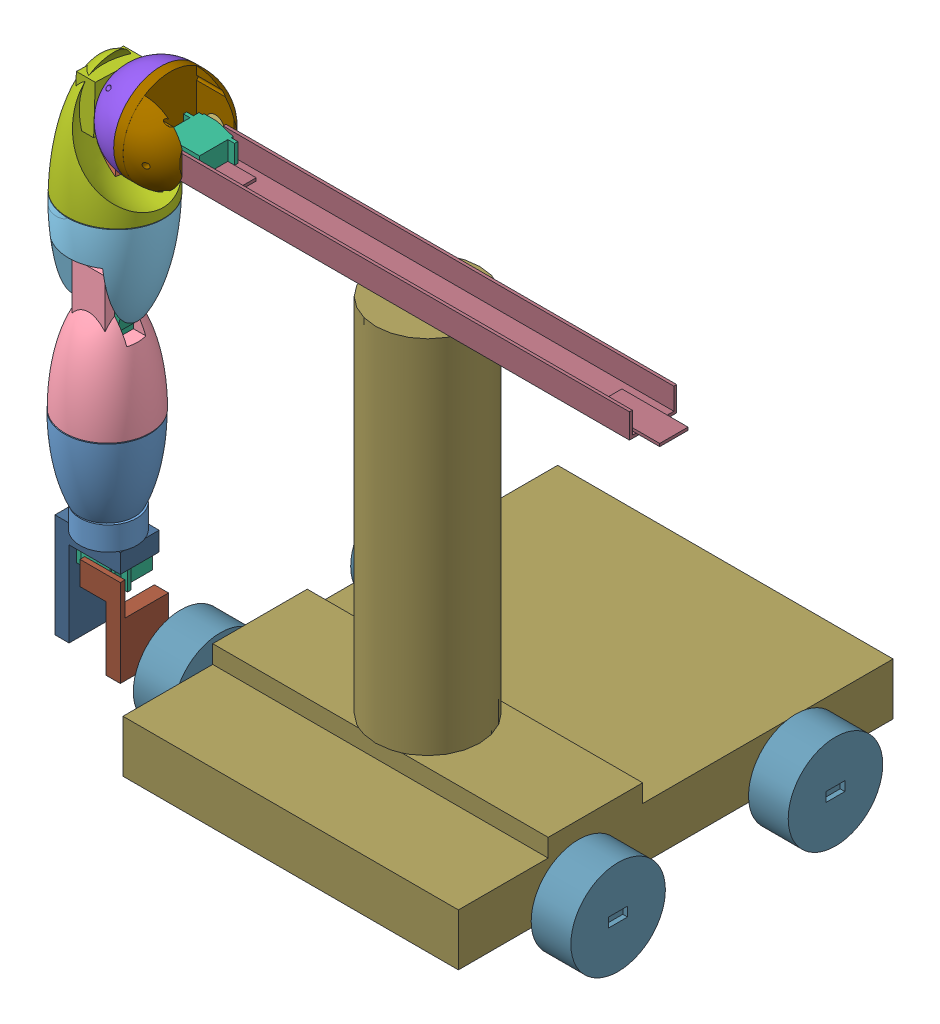
SolidWorks assembly Main-02, configuration Default. Lengths in mm.
Overall size (642.85 559.54 460).
33 component instances, 14 part files, 46 mates.
Components (placement in the parent):
- Part-Lower-2-1: Part-Lower-2 [Default] at (-289.0263 220.0038 50.0088) x (0 0 1) z (0 -1 0) size (90 90 228.56)
- Servo-01-1: Servo-01 [Default] at (-321.6816 280.1416 -12.7434) x (0 0 1) z (0 -1 0) size (27.63 54.2 54.1)
  - Servo-Body-2: Servo-Body [Default] at (17.7434 12.3164 23.3438) size (20.01 54.2 54.1)
  - Servo-Horn-2: Servo-Horn [Default] at (17.7434 12.3164 75.4438) x (-0.842157 -0.539233 0) z (0 0 1) size (20 20 5.5)
- Part-Lower-1-3: Part-Lower-1 [Default] at (-288.845 220.5616 -40) x (0 0 -1) z (0 1 0) size (90 90 141.99)
- Part-Upper-2-1: Part-Upper-2 [Default] at (-279.0096 422.4598 52.003) x (0 0.034316 0.999411) z (0 -0.999411 0.034316) size (100 99.78 127.75)
- Servo-02-1: Servo-02 [Default] at (-371.8086 355.927 -3.2932) x (0 0 1) z (1 0 0) size (20.01 54.2 48.1)
  - Servo-Body-6mm-1: Servo-Body-6mm [Default] at (8.2932 21.7501 21.9215) size (20.01 54.2 48.1)
  - Servo-Horn-1: Servo-Horn [Default] at (8.2932 21.7501 68.0215) size (20 20 5.5)
- Part-Upper-1-1: Part-Upper-1 [Left] at (-278.832 414.5851 1.5515) x (0 -0.034316 -0.999411) z (0 0.999411 -0.034316) size (139.94 103.76 247.91)
- Servo-01-4: Servo-01 [Default] at (-311.0982 480.2369 12.3085) x (-1 0 0) z (0 -0.999411 0.034316) size (27.63 54.2 54.1)
  - Servo-Body-2: Servo-Body [Default] at (17.7434 12.3164 23.3438) size (20.01 54.2 54.1)
  - Servo-Horn-2: Servo-Horn [Default] at (17.7434 12.3164 75.4438) x (-0.842157 -0.539233 0) z (0 0 1) size (20 20 5.5)
- Part-Shoulder-2-1: Part-Shoulder-2 [Left] at (-282.7416 557.2863 -143.6697) x (0 0 -1) z (-1 0 0) size (102.82 104.93 50.48)
- Servo-02-2: Servo-02 [Default] at (-260.8201 530.1527 7.2177) x (0 0 -1) z (-1 0 0) size (20.01 54.2 48.1)
  - Servo-Body-6mm-1: Servo-Body-6mm [Default] at (8.2932 21.7501 21.9215) size (20.01 54.2 48.1)
  - Servo-Horn-1: Servo-Horn [Default] at (8.2932 21.7501 68.0215) size (20 20 5.5)
- Part-Shoulder-1-1: Part-Shoulder-1 [Left] at (-284.157 607.5356 -15.41) x (0 0 1) z (1 0 0) size (102.75 100 51.7)
- Servo-02-3: Servo-02 [Default] at (-274.6292 495.7068 39.9215) x (0 1 0) z (0 0 -1) size (20.01 54.2 48.1)
  - Servo-Body-6mm-1: Servo-Body-6mm [Default] at (8.2932 21.7501 21.9215) size (20.01 54.2 48.1)
  - Servo-Horn-1: Servo-Horn [Default] at (8.2932 21.7501 68.0215) size (20 20 5.5)
- EE-Assembly-01-1: EE-Assembly-01 [Default] at (-293.4312 124.5369 -86.5401) x (-1 0 0) z (0 0 1) size (79.18 110 51.1)
  - EE-Part-1-1: EE-Part-1 [Default] at (45.9054 13.4136 84.1919) size (69.2 110 41.1)
  - EE-Part-2-1: EE-Part-2 [Default] at (69.0263 43.4136 127.0919) x (-1 0 0) z (0 -1 0) size (42.7 51.1 92.5)
  - Servo-02-1: Servo-02 [Default] at (7.2763 51.7068 44.0704) x (0 -1 0) z (0 0 1) size (20.01 54.2 48.1)
    - Servo-Body-6mm-1: Servo-Body-6mm [Default] at (8.2932 21.7501 21.9215) size (20.01 54.2 48.1)
    - Servo-Horn-1: Servo-Horn [Default] at (8.2932 21.7501 68.0215) size (20 20 5.5)
- Base-Part-01-1: Base-Part-01 [Default] at (-177.5 0 145) x (1 0 0) z (0 1 0) size (399 460 456)
- Base-Top-02-1: Base-Top-02 [Default] at (-177.5 0 145) x (1 0 0) z (0 1 0) size (527 50 36)
- Base-Wheel-01-1: Base-Wheel-01 [Default] at (189.5 50 -200) x (0 0 -1) z (1 0 0) size (100 100 42)
- Base-Wheel-01-2: Base-Wheel-01 [Default] at (189.5 50 30) x (0 0 -1) z (1 0 0) size (100 100 42)
- Base-Wheel-01-3: Base-Wheel-01 [Default] at (-189.5 50 30) x (0 0 1) z (-1 0 0) size (100 100 42)
- Base-Wheel-01-4: Base-Wheel-01 [Default] at (-189.5 50 -200) x (0 0 1) z (-1 0 0) size (100 100 42)
Mates (geometry in assembly coordinates):
- Coincident9: coincident anti-aligned: plane of Servo-01-1/Servo-Body-2 through (-333.9981 256.7978 -5) normal (0 0 -1); plane of Part-Lower-1-3 through (-360.9872 254.7978 -5) normal (0 0 1)
- Coincident10: coincident anti-aligned: plane of Servo-01-1/Servo-Body-2 through (-363.3772 256.7978 -5) normal (-1 0 0); plane of Part-Lower-1-3 through (-363.3772 254.7978 16) normal (1 0 0)
- Coincident12: coincident anti-aligned: plane of Servo-01-1/Servo-Body-2 through (-363.3772 226.7978 -12.914) normal (0 1 0); plane of Part-Lower-1-3 through (-288.845 226.7978 -40) normal (0 -1 0)
- Coincident13: coincident anti-aligned: plane of Servo-01-1/Servo-Body-2 through (-370.4772 226.7978 -12.914) normal (-1 0 0); plane of Part-Lower-1-3 through (-370.4772 196.111 -6) normal (1 0 0)
- Coincident29: coincident anti-aligned: plane of Part-Lower-1-3 through (-304.9872 345.7978 -5) normal (0 0 1); plane of Servo-02-1/Servo-Body-6mm-1 through (-349.8872 334.1769 -5) normal (0 0 -1)
- Coincident30: coincident anti-aligned: plane of Part-Lower-1-3 through (-304.9872 304.7978 -6) normal (0 1 0); plane of Servo-02-1/Servo-Body-6mm-1 through (-349.8872 304.7978 -5) normal (0 -1 0)
- Coincident31: coincident anti-aligned: plane of Part-Lower-1-3 through (-319.8872 218.8069 -6) normal (1 0 0); plane of Servo-02-1/Servo-Body-6mm-1 through (-319.8872 344.7978 -5) normal (-1 0 0)
- Coincident36: coincident anti-aligned: plane of Part-Lower-2-1 through (-333.9981 202.6978 5) normal (0 1 0); plane of Servo-01-1/Servo-Horn-2 through (-333.9981 202.6978 5) normal (0 -1 0)
- Concentric4: concentric anti-aligned: cylinder of Part-Lower-2-1 through (-333.9981 204.6978 5) axis (0 -1 0) radius 10; cylinder of Servo-01-1/Servo-Horn-2 through (-333.9981 202.6978 5) axis (0 1 0) radius 10
- Coincident37: coincident anti-aligned: plane of Part-Upper-2-1 through (-301.7872 294.3682 61.3993) normal (-1 0 0); plane of Servo-02-1/Servo-Horn-1 through (-301.7872 334.1769 5) normal (1 0 0)
- Concentric5: concentric anti-aligned: cylinder of Part-Upper-2-1 through (-303.7872 334.1769 5) axis (1 0 0) radius 10; cylinder of Servo-02-1/Servo-Horn-1 through (-301.7872 334.1769 5) axis (-1 0 0) radius 10
- Coincident42: coincident anti-aligned: plane of Part-Upper-1-1 through (-338.8416 409.8798 13.1279) normal (1 0 0); plane of Servo-01-4/Servo-Body-2 through (-338.8416 456.4842 0.8004) normal (-1 0 0)
- Coincident43: coincident anti-aligned: plane of Part-Upper-1-1 through (-317.8416 409.8764 13.0279) normal (0 -0.034316 -0.999411); plane of Servo-01-4/Servo-Body-2 through (-318.8416 456.8487 11.4151) normal (0 0.034316 0.999411)
- Coincident44: coincident anti-aligned: plane of Part-Upper-1-1 through (-328.8416 426.1526 -8.3432) normal (0 -0.999411 0.034316); plane of Servo-01-4/Servo-Body-2 through (-318.8416 426.8663 12.4445) normal (0 0.999411 -0.034316)
- Coincident45: coincident anti-aligned: plane of Part-Upper-2-1 through (-328.8416 402.4161 2.6569) normal (0 0.999411 -0.034316); plane of Servo-01-4/Servo-Horn-2 through (-328.8416 402.4161 2.6569) normal (0 -0.999411 0.034316)
- Concentric6: concentric anti-aligned: cylinder of Part-Upper-2-1 through (-328.8416 404.4149 2.5883) axis (0 -0.999411 0.034316) radius 10; cylinder of Servo-01-4/Servo-Horn-2 through (-328.8416 402.4161 2.6569) axis (0 0.999411 -0.034316) radius 10
- Coincident49: coincident anti-aligned: plane of Part-Upper-1-1 through (-330.8416 508.8144 10.9174) normal (1 0 0); plane of Servo-02-2/Servo-Horn-1 through (-330.8416 508.4026 -1.0755) normal (-1 0 0)
- Concentric7: concentric aligned: cylinder of Part-Upper-1-1 through (-331.8416 508.4026 -1.0755) axis (1 0 0) radius 10; cylinder of Servo-02-2/Servo-Horn-1 through (-330.8416 508.4026 -1.0755) axis (1 0 0) radius 10
- Coincident50: coincident anti-aligned: plane of Part-Shoulder-2-1 through (-312.7416 520.0235 8.9245) normal (0 0 -1); plane of Servo-02-2/Servo-Body-6mm-1 through (-282.7416 508.4026 8.9245) normal (0 0 1)
- Coincident51: coincident anti-aligned: plane of Part-Shoulder-2-1 through (-312.7416 519.0235 -12.0755) normal (0 -1 0); plane of Servo-02-2/Servo-Body-6mm-1 through (-282.7416 519.0235 8.9245) normal (0 1 0)
- Coincident52: coincident anti-aligned: plane of Part-Shoulder-2-1 through (-312.7416 495.8574 -12.0755) normal (-1 0 0); plane of Servo-02-2/Servo-Body-6mm-1 through (-312.7416 519.0235 8.9245) normal (1 0 0)
- Coincident58: coincident anti-aligned: plane of Part-Shoulder-2-1 through (-282.7416 507.2863 -0.4814) normal (1 0 0); plane of Part-Shoulder-1-1 through (-282.7416 507.3946 -0.4101) normal (-1 0 0)
- Coincident59: coincident aligned: plane of Part-Shoulder-2-1 through (-322.7416 558.0235 -47.0755) normal (0 0 -1); plane of Part-Shoulder-1-1 through (-232.8791 558.0235 -47.0755) normal (0 0 -1)
- Concentric11: concentric anti-aligned: cylinder of Part-Shoulder-2-1 through (-282.7416 538.0235 27.9245) axis (1 0 0) radius 2.5; cylinder of Part-Shoulder-1-1 through (-272.8791 538.0235 27.9245) axis (-1 0 0) radius 2.5
- Concentric12: concentric anti-aligned: cylinder of Part-Shoulder-2-1 through (-282.7416 538.0235 -27.0755) axis (1 0 0) radius 2.5; cylinder of Part-Shoulder-1-1 through (-231.042 538.0235 -27.0755) axis (-1 0 0) radius 2.5
- Concentric13: concentric anti-aligned: cylinder of Part-Shoulder-2-1 through (-282.7416 473.0235 -27.0755) axis (1 0 0) radius 2.5; cylinder of Part-Shoulder-1-1 through (-231.042 473.0235 -27.0755) axis (-1 0 0) radius 2.5
- Concentric14: concentric anti-aligned: cylinder of Part-Shoulder-2-1 through (-282.7416 473.0235 27.9245) axis (1 0 0) radius 2.5; cylinder of Part-Shoulder-1-1 through (-272.8791 473.0235 27.9245) axis (-1 0 0) radius 2.5
- Coincident60: coincident anti-aligned: plane of Part-Shoulder-1-1 through (-252.8791 501 -30.1) normal (0 0 1); plane of Servo-02-3/Servo-Horn-1 through (-252.8791 504 -30.1) normal (0 0 -1)
- Concentric15: concentric aligned: cylinder of Part-Shoulder-1-1 through (-252.8791 504 -28.1) axis (0 0 1) radius 10; cylinder of Servo-02-3/Servo-Horn-1 through (-252.8791 504 -30.1) axis (0 0 1) radius 10
- Coincident74: coincident anti-aligned: plane of Part-Lower-2-1 through (-319.3466 101.1233 -7.4982) normal (0 0 -1); plane of EE-Assembly-01-1/EE-Part-1-1 through (-346.8466 101.1233 -7.4982) normal (0 0 1)
- Coincident75: coincident anti-aligned: plane of Part-Lower-2-1 through (-289.0263 101.1233 50.0088) normal (0 -1 0); plane of EE-Assembly-01-1/EE-Part-1-1 through (-339.3366 101.1233 -2.3482) normal (0 1 0)
- Coincident76: coincident anti-aligned: plane of Part-Lower-2-1 through (-321.8466 101.1233 -9.9982) normal (1 0 0); plane of EE-Assembly-01-1/EE-Part-1-1 through (-321.8466 101.1233 -7.4982) normal (-1 0 0)
- Coincident78: coincident anti-aligned: plane of Base-Part-01-1 through (10 478 10) normal (0 0 -1); plane of Base-Top-02-1 through (-10 478 10) normal (0 0 1)
- Coincident79: coincident anti-aligned: plane of Base-Part-01-1 through (-10 478 -25) normal (1 0 0); plane of Base-Top-02-1 through (-10 478 -10) normal (-1 0 0)
- Coincident80: coincident anti-aligned: plane of Base-Part-01-1 through (-177.5 478 145) normal (0 1 0); plane of Base-Top-02-1 through (-177.5 478 145) normal (0 -1 0)
- Coincident81: coincident anti-aligned: plane of Base-Part-01-1 through (199.5 0 145) normal (1 0 0); plane of Base-Wheel-01-1 through (199.5 50 -200) normal (-1 0 0)
- Concentric16: concentric aligned: cylinder of Base-Part-01-1 through (199.5 50 -200) axis (-1 0 0) radius 4; cylinder of Base-Wheel-01-1 through (199.5 50 -200) axis (-1 0 0) radius 4
- Coincident82: coincident anti-aligned: plane of Base-Part-01-1 through (199.5 50 30) normal (1 0 0); plane of Base-Wheel-01-2 through (199.5 50 30) normal (-1 0 0)
- Concentric17: concentric aligned: cylinder of Base-Part-01-1 through (199.5 50 30) axis (-1 0 0) radius 4; cylinder of Base-Wheel-01-2 through (199.5 50 30) axis (-1 0 0) radius 4
- Coincident83: coincident anti-aligned: plane of Base-Part-01-1 through (-199.5 50 30) normal (-1 0 0); plane of Base-Wheel-01-3 through (-199.5 50 30) normal (1 0 0)
- Concentric18: concentric aligned: cylinder of Base-Part-01-1 through (-199.5 50 30) axis (1 0 0) radius 4; cylinder of Base-Wheel-01-3 through (-199.5 50 30) axis (1 0 0) radius 4
- Coincident84: coincident anti-aligned: plane of Base-Part-01-1 through (-199.5 50 -200) normal (-1 0 0); plane of Base-Wheel-01-4 through (-199.5 50 -200) normal (1 0 0)
- Concentric19: concentric aligned: cylinder of Base-Part-01-1 through (-199.5 50 -200) axis (1 0 0) radius 4; cylinder of Base-Wheel-01-4 through (-199.5 50 -200) axis (1 0 0) radius 4
- Coincident85: coincident aligned: plane of Servo-02-3/Servo-Body-6mm-1 through (-270.6 494 18) normal (0 0 1); plane of Base-Top-02-1 through (-193.5 494 18) normal (0 0 1)
- Coincident86: coincident anti-aligned: plane of Servo-02-3/Servo-Body-6mm-1 through (-252.8791 494 18) normal (0 -1 0); plane of Base-Top-02-1 through (-177.5 494 145) normal (0 1 0)
- Coincident87: coincident aligned: plane of Servo-02-3/Servo-Body-6mm-1 through (-263.5 494 18) normal (-1 0 0); plane of Base-Top-02-1 through (-263.5 494 15) normal (-1 0 0)
